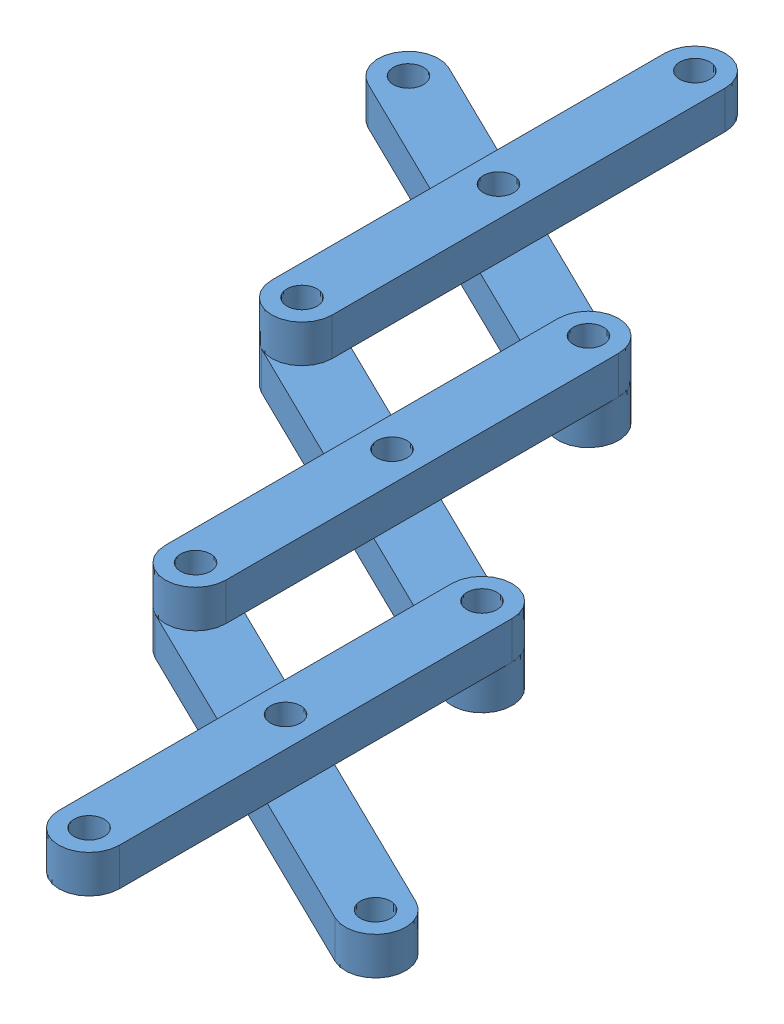
SolidWorks assembly Assem2, configuration Default. Lengths in mm.
Overall size (104.1 10 134.88).
6 component instances, 1 part files, 12 mates.
Components (placement in the parent):
- link-1: link [Default] at (-11.1875 -10.5583 11.3781) size (8 5 60)
- link-2: link [Default] at (-11.1875 -15.5583 11.3781) x (0.439932 0 -0.898031) z (0.898031 0 0.439932) size (8 5 60)
- link-3: link [Default] at (12.1613 -10.5583 48.8164) size (8 5 60)
- link-4: link [Default] at (12.1613 -15.5583 48.8164) x (0.439932 0 -0.898031) z (0.898031 0 0.439932) size (8 5 60)
- link-5: link [Default] at (35.5102 -10.5583 86.2546) size (8 5 60)
- link-6: link [Default] at (35.5102 -15.5583 86.2546) x (0.439932 0 -0.898031) z (0.898031 0 0.439932) size (8 5 60)
Mates (geometry in assembly coordinates):
- Concentric1: concentric aligned: cylinder of link-1 through (-11.1875 -5.5583 11.3781) axis (0 -1 0) radius 2; cylinder of link-2 through (-11.1875 -10.5583 11.3781) axis (0 -1 0) radius 2
- Coincident1: coincident anti-aligned: plane of link-1 through (-11.1875 -10.5583 37.3781) normal (0 -1 0); plane of link-2 through (12.1613 -10.5583 22.8164) normal (0 1 0)
- Concentric2: concentric aligned: cylinder of link-2 through (12.1613 -10.5583 22.8164) axis (0 -1 0) radius 2; cylinder of link-3 through (12.1613 -5.5583 22.8164) axis (0 -1 0) radius 2
- Coincident2: coincident aligned: plane of link-1 through (-11.1875 -5.5583 37.3781) normal (0 1 0); plane of link-3 through (12.1613 -5.5583 74.8164) normal (0 1 0)
- Concentric3: concentric aligned: cylinder of link-1 through (-11.1875 -5.5583 37.3781) axis (0 -1 0) radius 2; cylinder of link-4 through (-11.1875 -10.5583 37.3781) axis (0 -1 0) radius 2
- Coincident3: coincident anti-aligned: plane of link-1 through (-11.1875 -10.5583 37.3781) normal (0 -1 0); plane of link-4 through (35.5102 -10.5583 60.2546) normal (0 1 0)
- Concentric4: concentric aligned: cylinder of link-3 through (12.1613 -5.5583 48.8164) axis (0 -1 0) radius 2; cylinder of link-4 through (12.1613 -10.5583 48.8164) axis (0 -1 0) radius 2
- Concentric5: concentric aligned: cylinder of link-4 through (35.5102 -10.5583 60.2546) axis (0 -1 0) radius 2; cylinder of link-5 through (35.5102 -5.5583 60.2546) axis (0 -1 0) radius 2
- Coincident4: coincident aligned: plane of link-3 through (12.1613 -5.5583 74.8164) normal (0 1 0); plane of link-5 through (35.5102 -5.5583 112.2546) normal (0 1 0)
- Concentric6: concentric aligned: cylinder of link-3 through (12.1613 -5.5583 74.8164) axis (0 -1 0) radius 2; cylinder of link-6 through (12.1613 -10.5583 74.8164) axis (0 -1 0) radius 2
- Coincident5: coincident anti-aligned: plane of link-3 through (12.1613 -10.5583 74.8164) normal (0 -1 0); plane of link-6 through (58.859 -10.5583 97.6928) normal (0 1 0)
- Concentric7: concentric aligned: cylinder of link-5 through (35.5102 -5.5583 86.2546) axis (0 -1 0) radius 2; cylinder of link-6 through (35.5102 -10.5583 86.2546) axis (0 -1 0) radius 2
